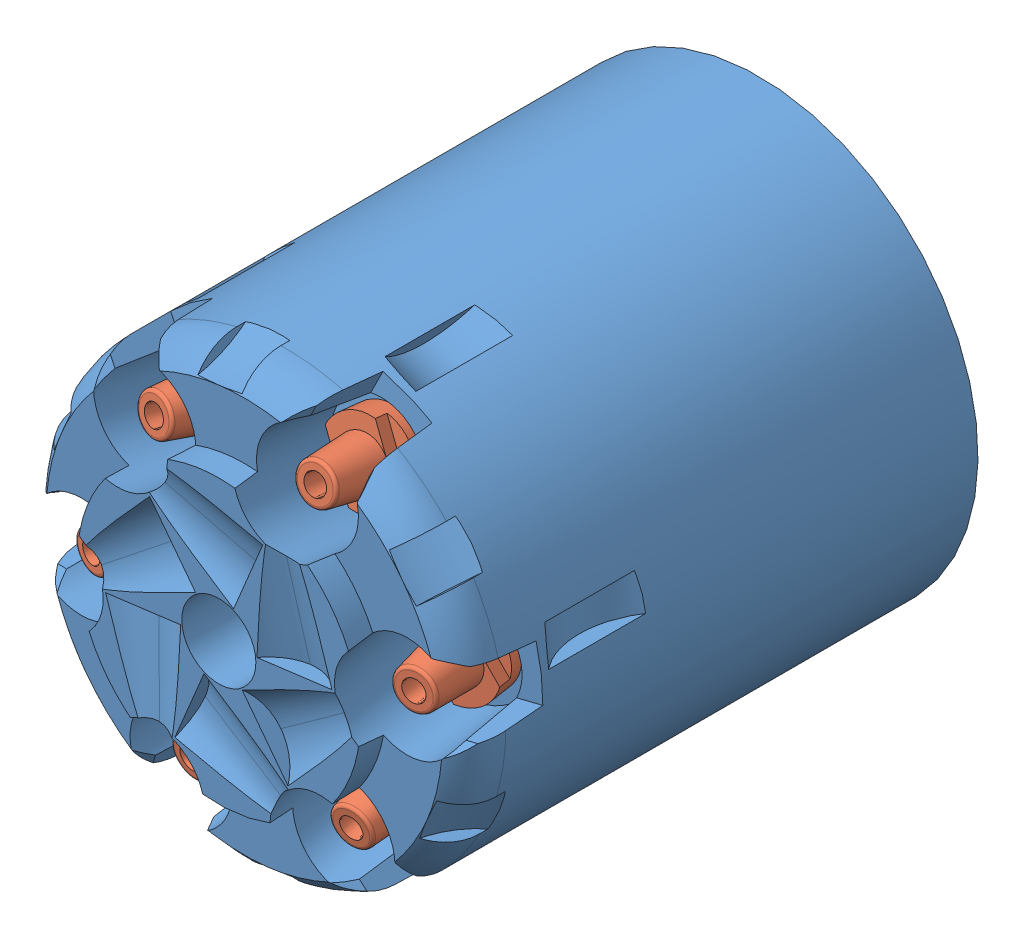
SolidWorks assembly Cylinder, configuration Default. Lengths in mm.
Overall size (68.62 86.03 77.72).
7 component instances, 2 part files, 12 mates.
Components (placement in the parent):
- Cylinder-1: Cylinder [Default] at (-77.5643 -305.0389 201.0524) x (0.14847 0.355565 -0.922784) z (0.922784 -0.385318 0) size (60.74 56.25 42.91)
- Nippel-2: Nippel [Default] at (-184.0015 -253.717 199.9332) x (0.304382 0.256744 -0.917297) z (0.740833 -0.669133 0.058542) size (12.39 9.96 7.5)
- Nippel-3: Nippel [Default] at (-188.5029 -282.288 165.4633) x (0.406043 0.319444 -0.856204) z (0.801927 -0.573836 0.166208) size (12.39 9.96 7.5)
- Nippel-4: Nippel [Default] at (-147.8434 -338.7334 114.0456) x (0.382353 0.500536 -0.776705) z (0.881426 -0.44983 0.144018) size (12.39 9.96 7.5)
- Nippel-7: Nippel [Default] at (-83.3295 -374.5993 82.4987) x (0.22941 0.637466 -0.735532) z (0.944815 -0.327421 0.010917) size (12.39 9.96 7.5)
- Nippel-8: Nippel [Default] at (-115.3345 -313.8727 174.9704) x (0.146174 0.431638 -0.890124) z (0.824191 -0.550777 -0.131736) size (12.39 9.96 7.5)
- Nippel-9: Nippel [Default] at (-93.9982 -360.822 108.6812) x (0.15195 0.597525 -0.787322) z (0.888904 -0.430903 -0.155471) size (12.39 9.96 7.5)
Mates (geometry in assembly coordinates):
- Concentric2: concentric: cylinder of Cylinder-1 through (7.8241 4.4065 31.9906) axis (-0.06691 -0.16024 -0.984808) radius 2.067; cylinder of Nippel-2 through (7.3691 3.3169 25.2939) axis (0.06691 0.16024 0.984808) radius 2.5
- Distance2: distance = 0 mm: plane of Nippel-2 through (8.7931 4.5741 23.8756) normal (-0.06691 -0.16024 -0.984808); plane of Cylinder-1 through (5.3881 3.9371 24.2106) normal (0.06691 0.16024 0.984808)
- Concentric3: concentric: cylinder of Cylinder-1 through (-7.5318 2.4294 31.9906) axis (0.105317 -0.138065 -0.984808) radius 2.067; cylinder of Nippel-3 through (-6.8157 1.4906 25.2939) axis (-0.105317 0.138065 0.984808) radius 2.5
- Distance3: distance = 0 mm: plane of Nippel-3 through (-5.3625 2.9556 24.1269) normal (0.105317 -0.138065 -0.984808); plane of Cylinder-1 through (-8.3433 0.0851 24.2106) normal (-0.105317 0.138065 0.984808)
- Concentric4: concentric: cylinder of Cylinder-1 through (-13.4976 -11.8577 31.9906) axis (0.172227 0.022174 -0.984808) radius 2.067; cylinder of Nippel-4 through (-12.3264 -11.7069 25.2939) axis (-0.172227 -0.022174 0.984808) radius 2.5
- Distance4: distance = 0 mm: plane of Nippel-4 through (-11.1 -9.87 24.4327) normal (0.172227 0.022174 -0.984808); plane of Cylinder-1 through (-11.873 -13.7326 24.2106) normal (-0.172227 -0.022174 0.984808)
- Concentric8: concentric: cylinder of Cylinder-1 through (-4.1074 -24.1678 31.9906) axis (0.06691 0.16024 -0.984808) radius 2.067; cylinder of Nippel-7 through (-3.6524 -23.0781 25.2939) axis (-0.06691 -0.16024 0.984808) radius 2.5
- Distance7: distance = 0 mm: plane of Nippel-7 through (-2.7832 -20.9929 24.5752) normal (0.06691 0.16024 -0.984808); plane of Cylinder-1 through (-1.6714 -23.6983 24.2106) normal (-0.06691 -0.16024 0.984808)
- Concentric9: concentric: cylinder of Cylinder-1 through (17.2142 -7.9035 31.9906) axis (-0.172227 -0.022174 -0.984808) radius 2.067; cylinder of Nippel-8 through (16.0431 -8.0543 25.2939) axis (0.172227 0.022174 0.984808) radius 2.5
- Distance8: distance = 0 mm: plane of Nippel-8 through (17.092 -6.4019 23.9562) normal (-0.172227 -0.022174 -0.984808); plane of Cylinder-1 through (15.5897 -6.0286 24.2106) normal (0.172227 0.022174 0.984808)
- Concentric10: concentric: cylinder of Cylinder-1 through (11.2485 -22.1907 31.9906) axis (-0.105317 0.138065 -0.984808) radius 2.067; cylinder of Nippel-9 through (11.1036 -22.0008 30.6364) axis (0.105317 -0.138065 0.984808) radius 2.5
- Distance9: distance = 0 mm: plane of Nippel-9 through (11.467 -19.2872 24.3524) normal (-0.105317 0.138065 -0.984808); plane of Cylinder-1 through (12.0599 -19.8463 24.2106) normal (0.105317 -0.138065 0.984808)
